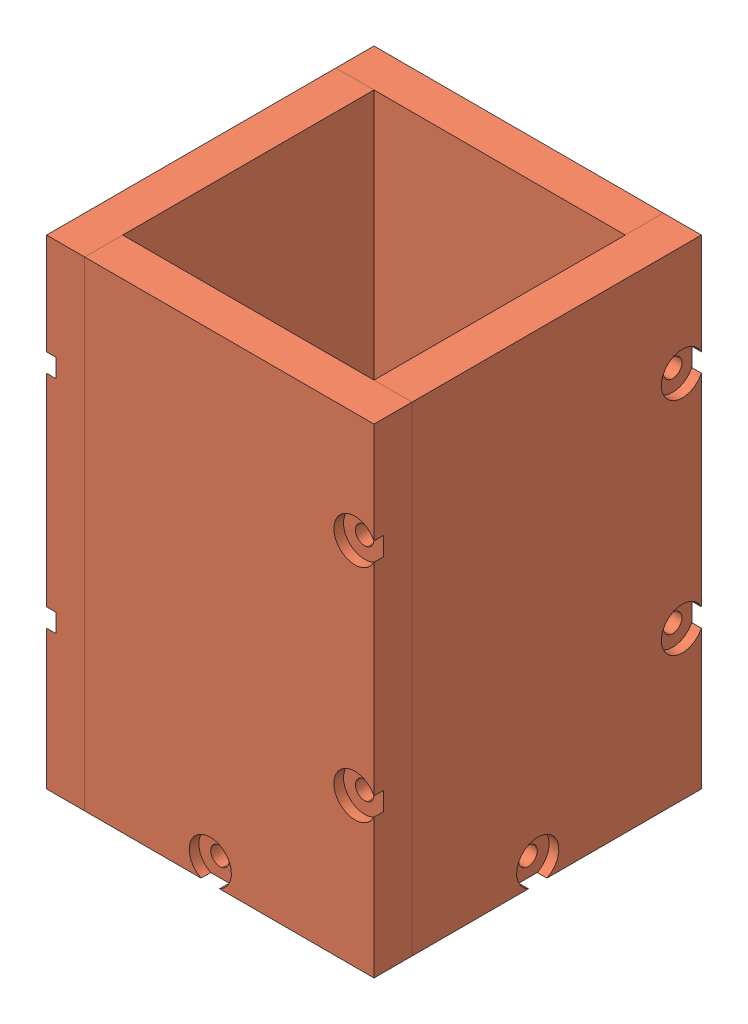
SolidWorks assembly waveguide_antenna_v1, configuration Default. Lengths in mm.
Overall size (43 63 43).
5 component instances, 2 part files, 10 mates.
Components (placement in the parent):
- backplate-1: backplate [Default] at origin size (33 5 33)
- sidewall-2: sidewall [Default] at (-21.5 31.5 2.5) x (0 -1 0) z (0 0 1) size (63 5 38)
- sidewall-3: sidewall [Default] at (2.5 31.5 21.5) x (0 -1 0) z (1 0 0) size (63 5 38)
- sidewall-4: sidewall [Default] at (21.5 31.5 -2.5) x (0 -1 0) z (0 0 -1) size (63 5 38)
- sidewall-6: sidewall [Default] at (-2.5 31.5 -21.5) x (0 -1 0) z (-1 0 0) size (63 5 38)
Mates (geometry in assembly coordinates):
- Concentric1: concentric aligned: circle of backplate-1; circle of sidewall-2
- Coincident1: coincident anti-aligned: line of backplate-1 through (-16.5 0 -16.5) axis (0 0 1); line of sidewall-2 through (-16.5 0 21.5) axis (0 0 -1)
- Concentric2: concentric aligned: circle of backplate-1; circle of sidewall-3
- Coincident2: coincident anti-aligned: line of backplate-1 through (-16.5 0 16.5) axis (1 0 0); line of sidewall-3 through (21.5 0 16.5) axis (-1 0 0)
- Concentric3: concentric aligned: circle of backplate-1; circle of sidewall-4
- Parallel1: parallel anti-aligned: line of sidewall-3 through (21.5 47.2869 21.5) axis (0 -1 0); line of sidewall-4 through (16.5 0 16.5) axis (0 1 0)
- Coincident6: coincident anti-aligned: line of backplate-1 through (16.5 0 16.5) axis (0 0 -1); line of sidewall-4 through (16.5 0 -21.5) axis (0 0 1)
- Concentric4: concentric: circle of backplate-1; circle of sidewall-6
- Coincident9: coincident: plane of sidewall-2 through (-21.5 31.5 2.5) normal (-1 0 0); line of sidewall-6 through (-21.5 63 -22.0128) axis (0 -1 0)
- Coincident10: coincident anti-aligned: line of sidewall-2 through (-21.5 0 -16.5) axis (0 1 0); line of sidewall-6 through (-21.5 63 -16.5) axis (0 -1 0)
